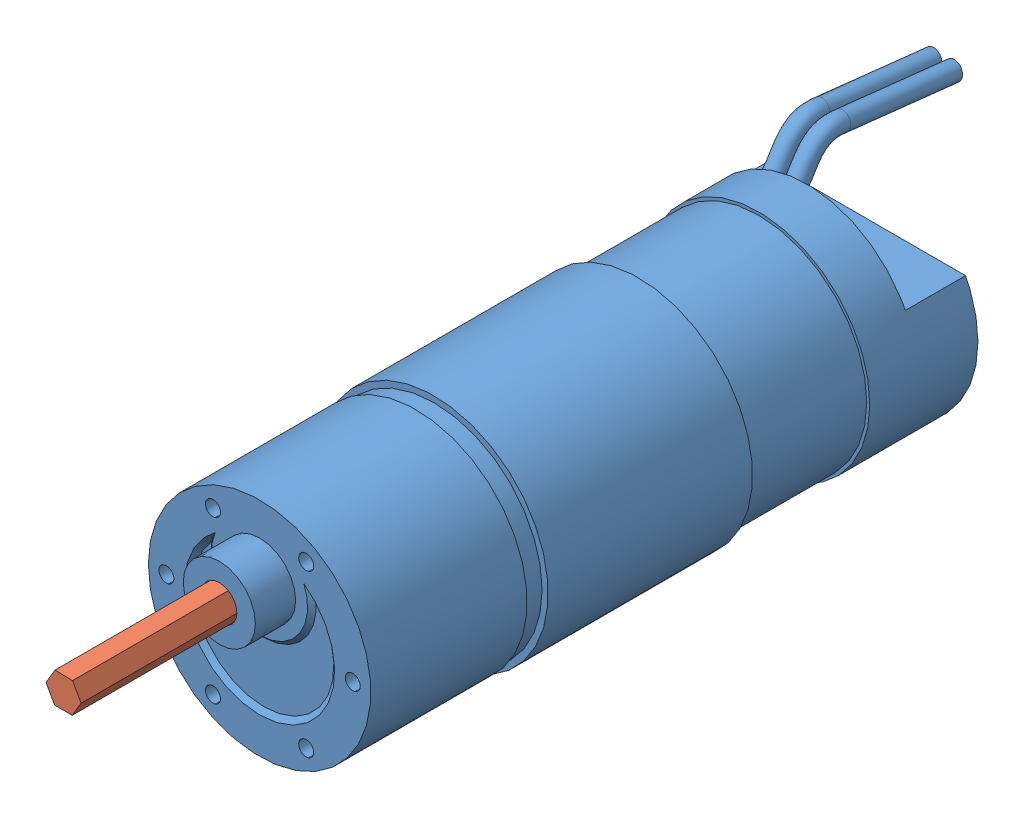
SolidWorks assembly PART_ASSEM_MotorHDHexRotating, configuration Default. Lengths in mm.
Overall size (38 39.44 154.16).
2 component instances, 2 part files, 3 mates.
Components (placement in the parent):
- PART_MotorHDHex_Shell-1: PART_MotorHDHex_Shell [Default] at (52.6409 85.4657 114.2715) size (38 39.44 128.25)
- PART_MotorHDHex_RotatingHex-1: PART_MotorHDHex_RotatingHex [Default] at (52.6787 94.995 172.8795) x (0.858442 -0.512911 0) z (0.512911 0.858442 0) size (5.06 33.53 5.84)
Mates (geometry in assembly coordinates):
- Coincident1: coincident anti-aligned: plane of PART_MotorHDHex_Shell-1 through (52.6409 92.4657 139.3515) normal (0 0 1); plane of PART_MotorHDHex_RotatingHex-1 through (52.6787 94.995 139.3515) normal (0 0 -1)
- Coincident2: coincident: cylinder of PART_MotorHDHex_Shell-1 through (52.6409 92.4657 139.3515) axis (0 0 1) radius 2.921; line of PART_MotorHDHex_RotatingHex-1 through (54.1391 94.9732 139.3515) axis (0 0 1)
- Coincident4: coincident: cylinder of PART_MotorHDHex_Shell-1 through (52.6409 92.4657 139.3515) axis (0 0 1) radius 2.921; line of PART_MotorHDHex_RotatingHex-1 through (51.2184 95.0169 139.3515) axis (0 0 1)
